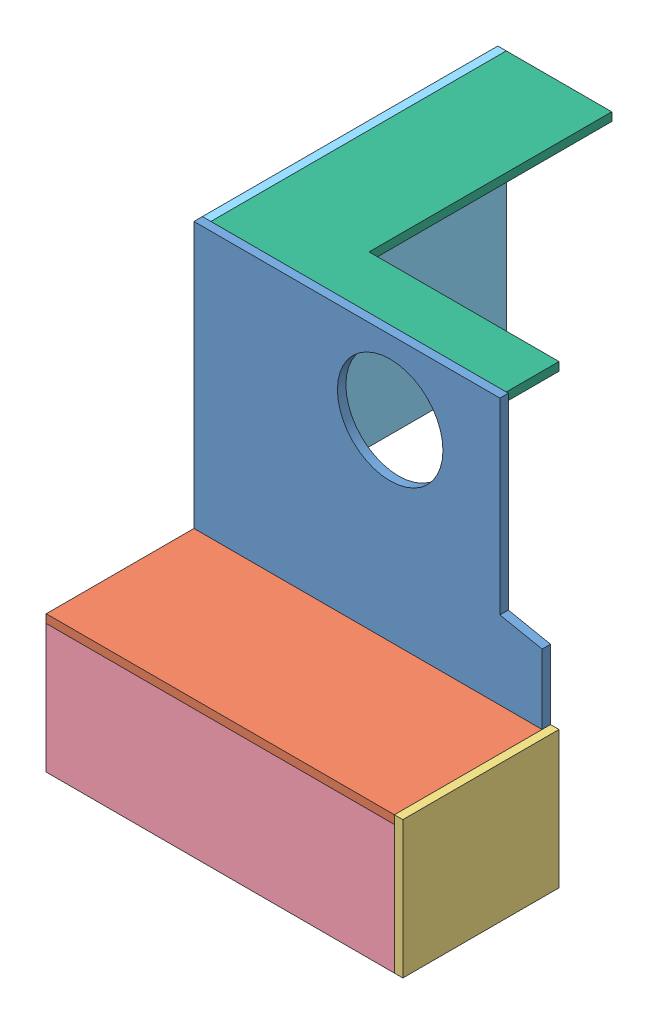
SolidWorks assembly cover, configuration По умолчанию. Lengths in mm.
Overall size (169 191 214).
6 component instances, 6 part files, 16 mates.
Components (placement in the parent):
- Part1-1: Part1 [Default] at origin size (165 130 4)
- Part2-1: Part2 [Default] at (0 0 39) x (1 0 0) z (0 1 0) size (165 70 4)
- Part3-1: Part3 [Default] at (86.5 -28.5 37) x (0 0 1) z (-1 0 0) size (74 65 4)
- Part4-1: Part4 [Default] at (0 -30.5 74) x (1 0 0) z (0 1 0) size (165 4 61)
- Part5-1: Part5 [Default] at (-82.5 65 -70) x (0 0 -1) z (1 0 0) size (140 130 4)
- Part6-1: Part6 [Default] at (-78.5 126 0) x (0 0 1) z (-1 0 0) size (140 4 140)
Mates (geometry in assembly coordinates):
- Coincident1: coordinate: point of Part1^cover-1
- Coincident2: coincident anti-aligned: plane of Part1^cover-1 through (0 0 4) normal (0 0 1); plane of Part2^cover-1 through (82.5 4 4) normal (0 0 -1)
- Coincident3: coincident aligned: plane of Part1^cover-1 through (82.5 37 4) normal (1 0 0); plane of Part2^cover-1 through (82.5 4 74) normal (1 0 0)
- Coincident4: coincident aligned: plane of Part1^cover-1 through (-82.5 0 4) normal (0 -1 0); plane of Part2^cover-1 through (0 0 39) normal (0 -1 0)
- Coincident5: coincident anti-aligned: plane of Part2^cover-1 through (82.5 4 74) normal (1 0 0); plane of Part3^cover-1 through (82.5 -28.5 37) normal (-1 0 0)
- Coincident6: coincident aligned: plane of Part2^cover-1 through (0 4 39) normal (0 1 0); plane of Part3^cover-1 through (82.5 4 0) normal (0 1 0)
- Coincident7: coincident aligned: plane of Part1^cover-1 through (0 0 0) normal (0 0 -1); plane of Part3^cover-1 through (82.5 -61 0) normal (0 0 -1)
- Coincident8: coincident anti-aligned: plane of Part2^cover-1 through (0 0 39) normal (0 -1 0); plane of Part4^cover-1 through (-82.5 0 70) normal (0 1 0)
- Coincident9: coincident anti-aligned: plane of Part3^cover-1 through (82.5 -28.5 37) normal (-1 0 0); plane of Part4^cover-1 through (82.5 0 70) normal (1 0 0)
- Coincident10: coincident aligned: plane of Part2^cover-1 through (82.5 4 74) normal (0 0 1); plane of Part4^cover-1 through (0 -30.5 74) normal (0 0 1)
- Coincident11: coincident aligned: plane of Part1^cover-1 through (-82.5 0 4) normal (-1 0 0); plane of Part5^cover-1 through (-82.5 65 -70) normal (-1 0 0)
- Coincident12: coincident anti-aligned: plane of Part1^cover-1 through (0 0 0) normal (0 0 -1); plane of Part5^cover-1 through (-78.5 0 0) normal (0 0 1)
- Coincident13: coincident aligned: plane of Part1^cover-1 through (-82.5 130 4) normal (0 1 0); plane of Part5^cover-1 through (-78.5 130 0) normal (0 1 0)
- Coincident14: coincident anti-aligned: plane of Part1^cover-1 through (0 0 0) normal (0 0 -1); plane of Part6^cover-1 through (61.5 130 0) normal (0 0 1)
- Coincident15: coincident aligned: plane of Part1^cover-1 through (-82.5 130 4) normal (0 1 0); plane of Part6^cover-1 through (-78.5 130 0) normal (0 1 0)
- Coincident16: coincident anti-aligned: plane of Part5^cover-1 through (-78.5 65 -70) normal (1 0 0); plane of Part6^cover-1 through (-78.5 130 0) normal (-1 0 0)
